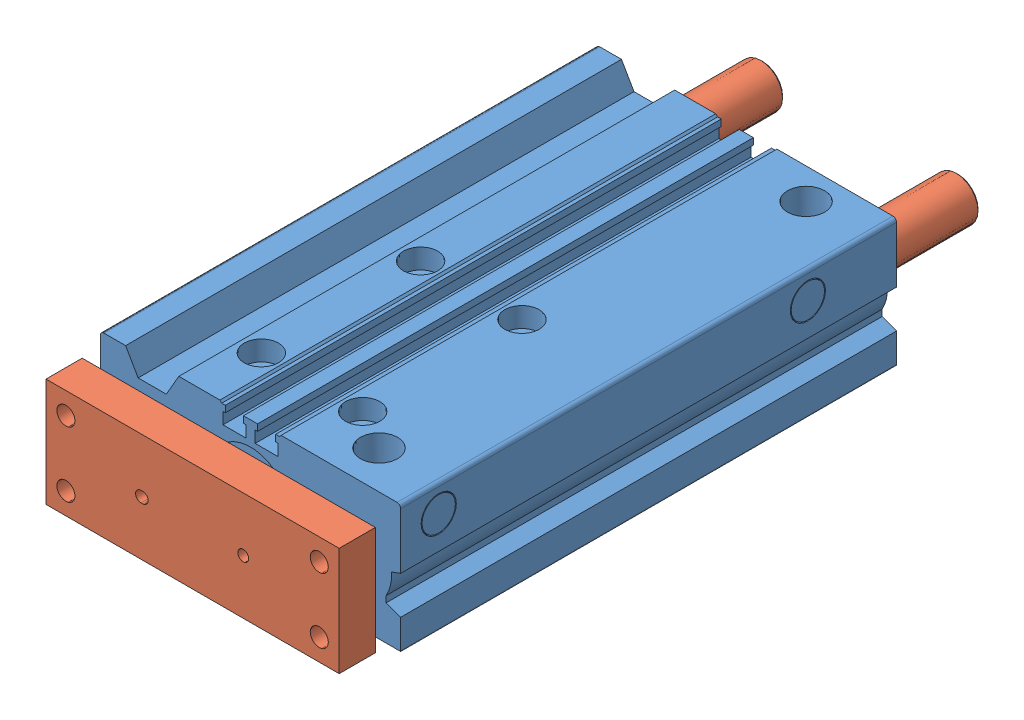
SolidWorks assembly CYLINDER ASSEMBLY, configuration MGPM20N-100. Lengths in mm.
Overall size (83 36 184.5).
2 component instances, 2 part files, 3 mates.
Components (placement in the parent):
- R&D5321-31 SMC MGPM20N-100_MGPTube-1: R&D5321-31 SMC MGPM20N-100_MGPTube [20M] at origin size (83 36 137)
- R&D5321-31 SMC MGPM20N-100_MGPRod-1: R&D5321-31 SMC MGPM20N-100_MGPRod [20M] at (0 0 -52.5) size (81 30 184.5)
Mates (geometry in assembly coordinates):
- Concentric1: concentric: cylinder of R&D5321-31 SMC MGPM20N-100_MGPTube-1 through (0 0 -14.2836) axis (0 0 1) radius 5.05; cylinder of R&D5321-31 SMC MGPM20N-100_MGPRod-1 through (0 0 88.6421) axis (0 0 -1) radius 5
- Parallel1: parallel: plane of R&D5321-31 SMC MGPM20N-100_MGPRod-1 through (0 0 -52.5) normal (0 1 0); plane of assembly through (0 0 0) normal (0 1 0)
- LimitDistance1: limit distance = 6 mm: plane of R&D5321-31 SMC MGPM20N-100_MGPTube-1 through (0 0 68.5) normal (0 0 1); plane of R&D5321-31 SMC MGPM20N-100_MGPRod-1 through (-40.5 -15 74.5) normal (0 0 -1)
